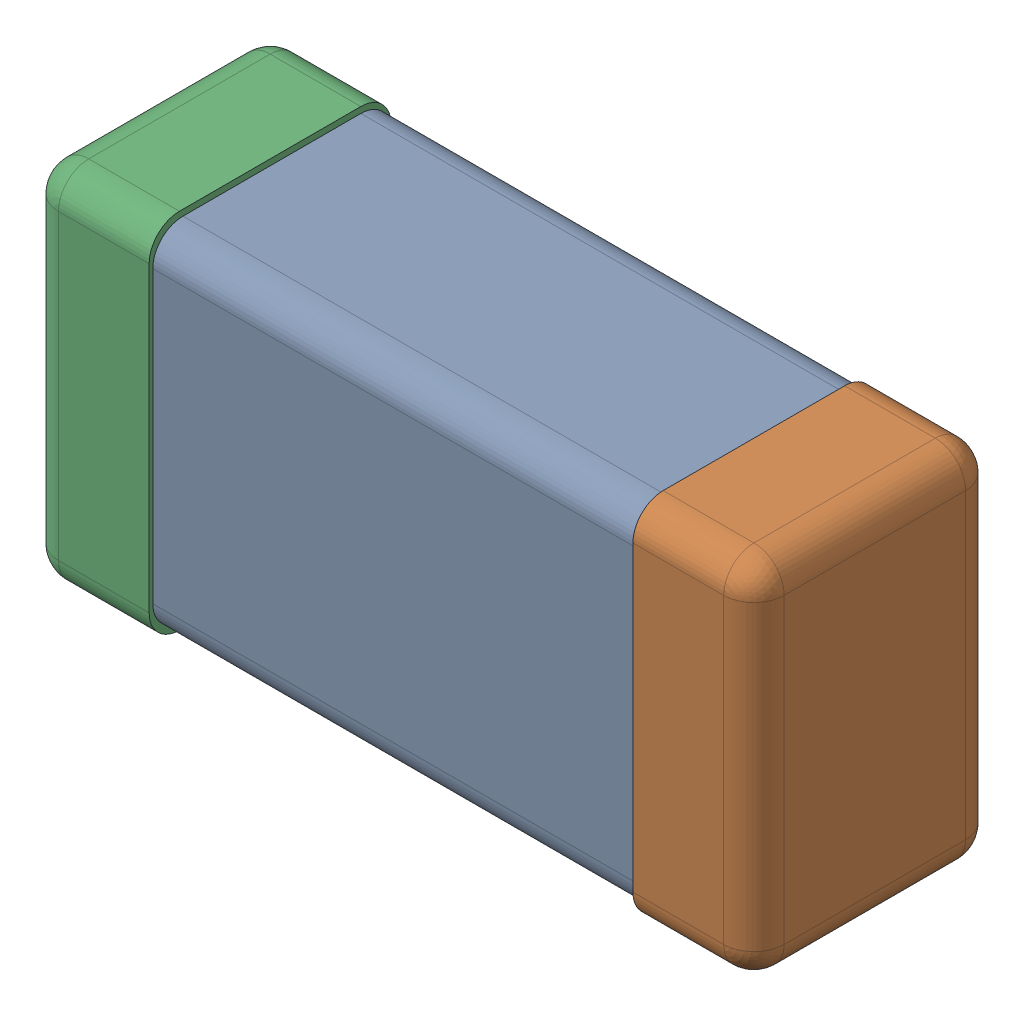
SolidWorks assembly C0201_020_30, configuration Standard. Lengths in mm.
Overall size (0.6 0.3 0.2).
4 component instances, 3 part files, 0 mates.
Components (placement in the parent):
- C0201_020_31-1: C0201_020_31 [Standard] at origin size (0.6 0.3 0.2)
  - Part 3_2-1: Part 3_2 [Standard] at (0 0 -7.3015) size (0.5 0.29 0.2)
  - Part 2_2-1: Part 2_2 [Standard] at (0 0 -7.3) size (0.1 0.3 0.2)
  - Part 1_2-1: Part 1_2 [Standard] at (0 0 -7.3) size (0.1 0.3 0.2)
